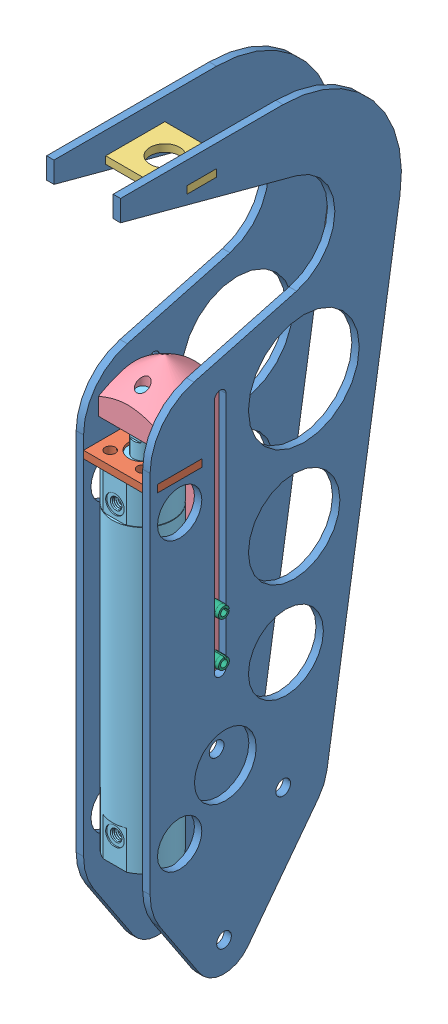
SolidWorks assembly Climb Hook, configuration Default. Lengths in mm.
Overall size (34.92 310.69 120.65).
8 component instances, 6 part files, 23 mates.
Components (placement in the parent):
- Climb Hook Body Plate 1.1-1: Climb Hook Body Plate 1.1 [Default] at (12.7 0 0) size (3.17 310.69 120.65)
- Climb Hook Body Plate 1.1-2: Climb Hook Body Plate 1.1 [Default] at (-15.875 0 0) size (3.17 310.69 120.65)
- Climb Hook Latch Plate-1: Climb Hook Latch Plate [Default] at (0 136.525 44.45) size (31.75 3.17 25.4)
- Climb Hook Latch Lock Plate-1: Climb Hook Latch Lock Plate [Default] at (0 241.3 34.925) size (31.75 3.17 25.4)
- Climb Hook Latch-1: Climb Hook Latch [Default] at (0 149.225 31.115) size (25.4 116.84 28.58)
- 6471K103_Impact-Resistant Round Body Air Cylinder-1: 6471K103_Impact-Resistant Round Body Air Cylinder [Retracted] at (0 63.881 44.45) x (0 -1 0) z (0 0 -1) size (173.05 25.91 25.91)
- 98296A913_1050-1095 Spring Steel Slotted Spring Pin-1: 98296A913_1050-1095 Spring Steel Slotted Spring Pin [98296A913] at (0 79.375 26.9875) x (0 0 1) z (-1 0 0) size (4.89 4.93 34.92)
- 98296A913_1050-1095 Spring Steel Slotted Spring Pin-2: 98296A913_1050-1095 Spring Steel Slotted Spring Pin [98296A913] at (0 60.325 26.9875) x (0 -0.967924 0.251242) z (-1 0 0) size (4.89 4.93 34.92)
Mates (geometry in assembly coordinates):
- Symmetric1: symmetric aligned: plane of Climb Hook Body Plate 1.1-1 through (12.7 203.2 0) normal (-1 0 0); plane of Climb Hook Body Plate 1.1-2 through (-12.7 203.2 0) normal (1 0 0)
- Concentric1: concentric aligned: cylinder of Climb Hook Body Plate 1.1-1 through (15.875 0 0) axis (-1 0 0) radius 3.175; cylinder of Climb Hook Body Plate 1.1-2 through (-12.7 0 0) axis (-1 0 0) radius 3.175
- Coincident1: coincident aligned: plane of Climb Hook Body Plate 1.1-1 through (15.875 -11.4025 57.15) normal (0 0 1); plane of Climb Hook Body Plate 1.1-2 through (-12.7 -11.4025 57.15) normal (0 0 1)
- Parallel1: parallel aligned: plane of Climb Hook Body Plate 1.1-1 through (15.875 -11.4025 57.15) normal (0 0 1)
- Coincident4: coincident: line of Climb Hook Body Plate 1.1-1 through (0 3.175 15.875) axis (0 0 -1)
- Coincident5: coincident: line of Climb Hook Body Plate 1.1-1 through (0 3.175 15.875) axis (0 0 -1)
- Coincident6: coincident anti-aligned: plane of Climb Hook Body Plate 1.1-2 through (-12.7 203.2 0) normal (1 0 0); plane of Climb Hook Latch Plate-1 through (-12.7 139.7 57.15) normal (-1 0 0)
- Coincident7: coincident anti-aligned: plane of Climb Hook Body Plate 1.1-1 through (12.7 203.2 0) normal (-1 0 0); plane of Climb Hook Latch Plate-1 through (12.7 139.7 57.15) normal (1 0 0)
- Coincident8: coincident anti-aligned: plane of Climb Hook Body Plate 1.1-1 through (15.875 136.525 53.975) normal (0 1 0); plane of Climb Hook Latch Plate-1 through (0 136.525 44.45) normal (0 -1 0)
- Coincident9: coincident anti-aligned: plane of Climb Hook Body Plate 1.1-1 through (15.875 139.7 53.975) normal (0 0 -1); plane of Climb Hook Latch Plate-1 through (15.875 139.7 53.975) normal (0 0 1)
- Coincident10: coincident anti-aligned: plane of Climb Hook Body Plate 1.1-1 through (15.875 241.3 41.275) normal (0 1 0); plane of Climb Hook Latch Lock Plate-1 through (0 241.3 34.925) normal (0 -1 0)
- Coincident11: coincident anti-aligned: plane of Climb Hook Body Plate 1.1-1 through (12.7 203.2 0) normal (-1 0 0); plane of Climb Hook Latch Lock Plate-1 through (12.7 244.475 47.625) normal (1 0 0)
- Coincident12: coincident anti-aligned: plane of Climb Hook Body Plate 1.1-1 through (15.875 241.3 41.275) normal (0 0 -1); plane of Climb Hook Latch Lock Plate-1 through (12.7 244.475 41.275) normal (0 0 1)
- Parallel2: parallel anti-aligned: plane of Climb Hook Body Plate 1.1-1 through (12.7 203.2 0) normal (-1 0 0); plane of Climb Hook Latch-1 through (12.7 149.225 31.115) normal (1 0 0)
- Concentric4: concentric anti-aligned: cylinder of Climb Hook Latch Plate-1 through (0 136.525 44.45) axis (0 1 0) radius 6; cylinder of 6471K103_Impact-Resistant Round Body Air Cylinder-1 through (0 138.557 44.45) axis (0 -1 0) radius 5.9944
- Coincident15: coincident anti-aligned: plane of Climb Hook Latch Plate-1 through (0 136.525 44.45) normal (0 -1 0); plane of 6471K103_Impact-Resistant Round Body Air Cylinder-1 through (0 136.525 44.45) normal (0 1 0)
- Concentric5: concentric anti-aligned: cylinder of Climb Hook Latch-1 through (0 149.225 44.45) axis (0 -1 0) radius 2.5527; cylinder of 6471K103_Impact-Resistant Round Body Air Cylinder-1 through (0 36.957 44.45) axis (0 1 0) radius 4.0005
- Coincident16: coincident anti-aligned: plane of Climb Hook Latch-1 through (12.7 149.225 50.8) normal (0 -1 0); plane of 6471K103_Impact-Resistant Round Body Air Cylinder-1 through (0 149.225 44.45) normal (0 1 0)
- Perpendicular1: perpendicular: plane of Climb Hook Body Plate 1.1-1 through (12.7 203.2 0) normal (-1 0 0); plane of 6471K103_Impact-Resistant Round Body Air Cylinder-1 through (5.0289 120.123 32.512) normal (0 0 -1)
- Concentric6: concentric anti-aligned: cylinder of Climb Hook Latch-1 through (12.7 79.375 26.9875) axis (1 0 0) radius 2.3813; cylinder of 98296A913_1050-1095 Spring Steel Slotted Spring Pin-1 through (17.4625 79.375 26.9875) axis (-1 0 0) radius 2.4638
- Width1: width anti-aligned: plane of 98296A913_1050-1095 Spring Steel Slotted Spring Pin-1 through (17.4625 79.375 26.9875) normal (1 0 0); plane of Climb Hook Latch-1 through (-17.4625 79.375 26.9875) normal (-1 0 0); plane of 98296A913_1050-1095 Spring Steel Slotted Spring Pin-1 through (-12.7 149.225 31.115) normal (-1 0 0); plane of Climb Hook Latch-1 through (12.7 149.225 31.115) normal (1 0 0)
- Concentric7: concentric anti-aligned: cylinder of Climb Hook Latch-1 through (12.7 60.325 26.9875) axis (1 0 0) radius 2.3813; cylinder of 98296A913_1050-1095 Spring Steel Slotted Spring Pin-2 through (17.4625 60.325 26.9875) axis (-1 0 0) radius 2.4638
- Width2: width anti-aligned: plane of 98296A913_1050-1095 Spring Steel Slotted Spring Pin-2 through (17.4625 60.325 26.9875) normal (1 0 0); plane of Climb Hook Latch-1 through (-17.4625 60.325 26.9875) normal (-1 0 0); plane of 98296A913_1050-1095 Spring Steel Slotted Spring Pin-2 through (-12.7 149.225 31.115) normal (-1 0 0); plane of Climb Hook Latch-1 through (12.7 149.225 31.115) normal (1 0 0)
